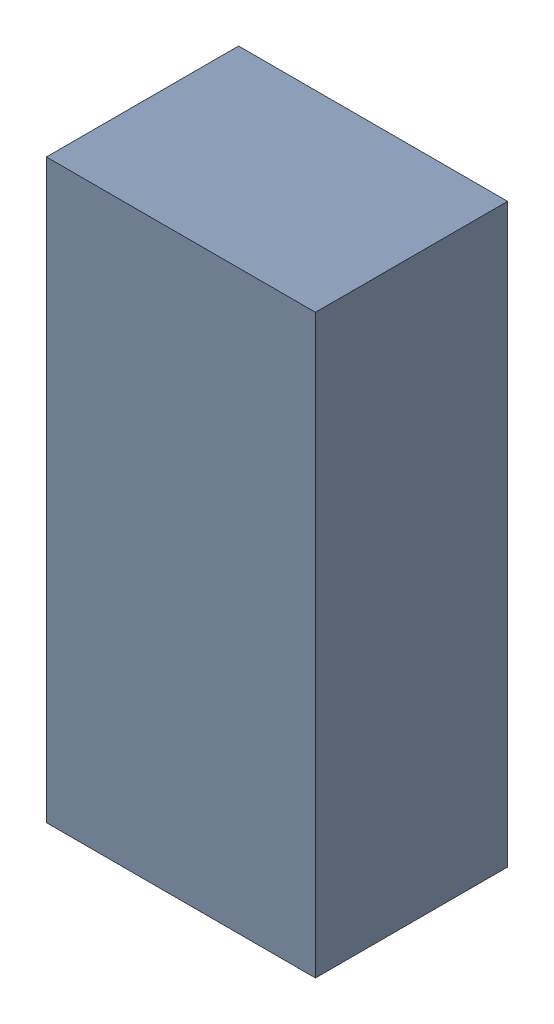
SolidWorks assembly Q3, configuration Default. Lengths in mm.
Overall size (1.4 3 1).
2 component instances, 1 part files, 0 mates.
Components (placement in the parent):
- 959206624-1: 959206624 [Default] at (105.664 90.805 0.1) size (1.4 3 1)
  - Extruded-10-1: Extruded-10 [Default] at origin size (1.4 3 1)
